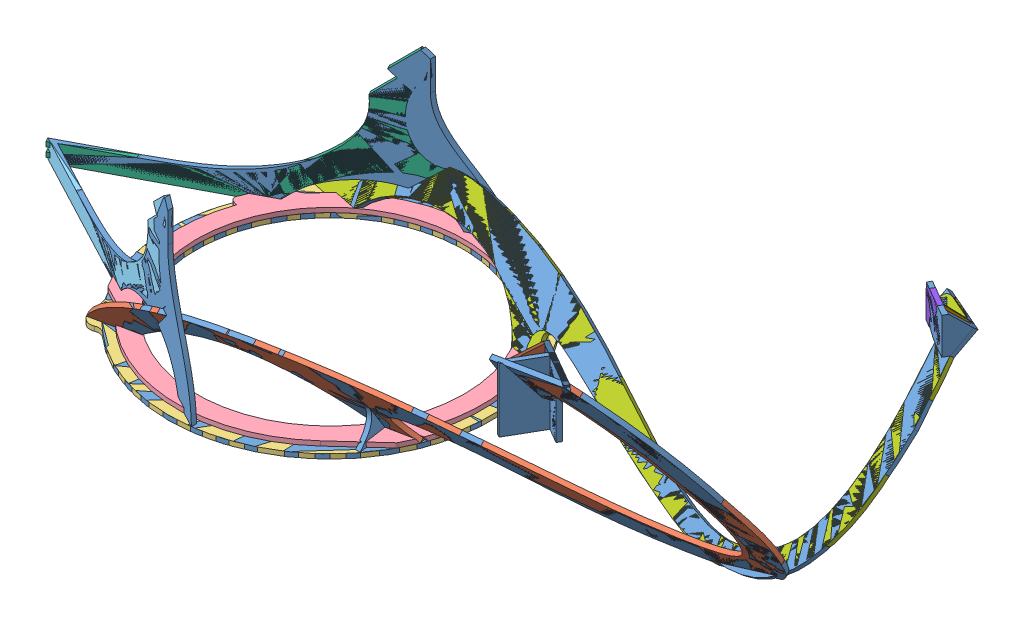
SolidWorks assembly Plywood, configuration Default. Lengths in mm.
Overall size (1757.07 753.37 1025.58).
11 component instances, 11 part files, 22 mates.
Components (placement in the parent):
- Plywood Construction-1-1: Plywood Construction-1 [Default] at (-484.877 -194.9913 42.0018) size (1754.25 687.65 739.41)
- Left side-1: Left side [Default] at (-1178.3167 284.2473 686.8396) x (0.984015 0.049102 -0.17118) z (0.17118 -0.525834 0.833185) size (1351.9 560.44 10)
- Circular Base-1: Circular Base [Default] at (-484.877 -204.9913 42.0018) size (711 10 711)
- Circular Base layer 2-1: Circular Base layer 2 [Default] at (-484.877 -184.9913 42.0018) x (1 0 0) z (0 -1 0) size (674.73 670 10)
- mirror Support-1: mirror Support [Default] at (-592.8492 -36.9594 301.6177) x (0.884433 0 0.466667) z (-0.466667 0 0.884433) size (627.88 342.07 10)
- mirror Support 2-1: mirror Support 2 [Default] at (-592.8492 -36.9594 385.6212) x (0.884433 0 0.466667) z (-0.466667 0 0.884433) size (376.34 342.07 538.3)
- Right Side-1: Right Side [Default] at (-540.945 -112.7648 -223.2928) x (0.985842 0.055197 0.158332) z (-0.158332 0.617278 0.770648) size (1400.58 563.91 10)
- Right axle plate-1: Right axle plate [Default] at (586.5901 210.0087 -229.6489) x (0.866025 0 0.5) z (0 -1 0) size (93.54 10 75.6)
- Right back plate-1: Right back plate [Default] at (589.3166 246.8548 -216.5277) x (0.27314 -0.94896 0.157698) z (-0.5 0 0.866025) size (83.03 10 55.83)
- left axle plate-1: left axle plate [Default] at (277.915 210.0087 304.9922) x (0.866025 0 0.5) z (-0.5 0 0.866025) size (124.63 140 10)
- Left back plate-1: Left back plate [Default] at (270.8642 114.8019 300.9214) x (-0.5 0 0.866025) z (-0.845415 -0.216867 -0.488101) size (84.72 140.72 10)
Mates (geometry in assembly coordinates):
- Coincident1: coincident aligned: plane of Plywood Construction-1-1 through (-263.2818 -64.0221 279.046) normal (0.17118 -0.525834 0.833185); plane of Left side-1 through (-1178.3167 284.2473 686.8396) normal (0.17118 -0.525834 0.833185)
- Coincident2: coincident aligned: plane of Plywood Construction-1-1 through (-484.877 -194.9913 42.0018) normal (0 1 0); plane of Circular Base-1 through (-484.877 -194.9913 42.0018) normal (0 1 0)
- Concentric1: concentric aligned: circle of Plywood Construction-1-1; circle of Circular Base-1
- Coincident3: coincident aligned: plane of Plywood Construction-1-1 through (-484.877 -194.9913 42.0018) normal (0 0 1); plane of Circular Base-1 through (-484.877 -204.9913 42.0018) normal (0 0 1)
- Coincident4: coincident anti-aligned: plane of Circular Base-1 through (-484.877 -194.9913 42.0018) normal (0 1 0); plane of Circular Base layer 2-1 through (-484.877 -194.9913 42.0018) normal (0 -1 0)
- Concentric2: concentric anti-aligned: circle of Circular Base-1; circle of Circular Base layer 2-1
- Coincident6: coincident anti-aligned: plane of Plywood Construction-1-1 through (-1084.877 175.0087 42.0018) normal (0.466667 0 -0.884433); plane of mirror Support-1 through (-592.8492 -36.9594 301.6177) normal (-0.466667 0 0.884433)
- Coincident7: coincident aligned: plane of Plywood Construction-1-1 through (-1106.3056 175.0087 42.0018) normal (-0.466667 0 -0.884433); plane of mirror Support 2-1 through (-768.174 -128.3642 -136.4116) normal (-0.466667 0 -0.884433)
- Coincident8: coincident anti-aligned: plane of Circular Base-1 through (-484.877 -194.9913 42.0018) normal (0 1 0); plane of mirror Support 2-1 through (-1106.3056 -194.9913 42.0018) normal (0 -1 0)
- Coincident12: coincident: point of Plywood Construction-1-1; point of mirror Support 2-1
- Coincident13: coincident aligned: plane of Plywood Construction-1-1 through (-775.2678 -233.8883 -174.4168) normal (-0.158332 0.617278 0.770648); plane of Right Side-1 through (-540.945 -112.7648 -223.2928) normal (-0.158332 0.617278 0.770648)
- Concentric3: concentric anti-aligned: circle of Plywood Construction-1-1; cylinder of Right axle plate-1 through (581.5901 210.0087 -220.9886) axis (0.5 0 -0.866025) radius 5
- Parallel1: parallel aligned: plane of Plywood Construction-1-1 through (620.5613 250.0087 -198.4886) normal (0 1 0); plane of Right axle plate-1 through (538.2889 250.0087 -245.9886) normal (0 1 0)
- Coincident15: coincident aligned: plane of Plywood Construction-1-1 through (616.901 250.0087 -212.1489) normal (0.5 0 -0.866025); plane of Right axle plate-1 through (593.6087 177.4307 -225.5967) normal (0.5 0 -0.866025)
- Coincident16: coincident aligned: plane of Right axle plate-1 through (619.2934 174.4136 -199.2206) normal (0.821824 0.315395 0.47448); plane of Right back plate-1 through (605.2662 240.5191 -218.8662) normal (0.821824 0.315395 0.47448)
- Coincident17: coincident aligned: plane of Right axle plate-1 through (588.6087 177.4307 -216.9364) normal (-0.5 0 0.866025); plane of Right back plate-1 through (600.2662 240.5191 -210.206) normal (-0.5 0 0.866025)
- Concentric4: concentric anti-aligned: circle of Plywood Construction-1-1; circle of left axle plate-1
- Coincident18: coincident aligned: plane of Plywood Construction-1-1 through (277.915 250.0087 304.9922) normal (0.5 0 -0.866025); plane of left axle plate-1 through (303.5733 250.0087 319.806) normal (0.5 0 -0.866025)
- Parallel2: parallel aligned: plane of Plywood Construction-1-1 through (262.915 250.0087 296.3319) normal (0 1 0); plane of left axle plate-1 through (335.5748 250.0087 349.8291) normal (0 1 0)
- Coincident20: coincident anti-aligned: plane of left axle plate-1 through (250.7031 193.6053 300.8284) normal (-0.845415 -0.216867 -0.488101); plane of Left back plate-1 through (244.4344 252.1774 285.6621) normal (0.845415 0.216867 0.488101)
- Coincident21: coincident anti-aligned: plane of left axle plate-1 through (234.7365 230.4847 291.61) normal (0.187812 -0.976201 0.108434); plane of Left back plate-1 through (248.1906 232.6534 287.8308) normal (-0.187812 0.976201 -0.108434)
- Coincident22: coincident aligned: plane of left axle plate-1 through (303.5733 250.0087 319.806) normal (0.5 0 -0.866025); plane of Left back plate-1 through (262.4101 112.6332 296.0404) normal (0.5 0 -0.866025)
